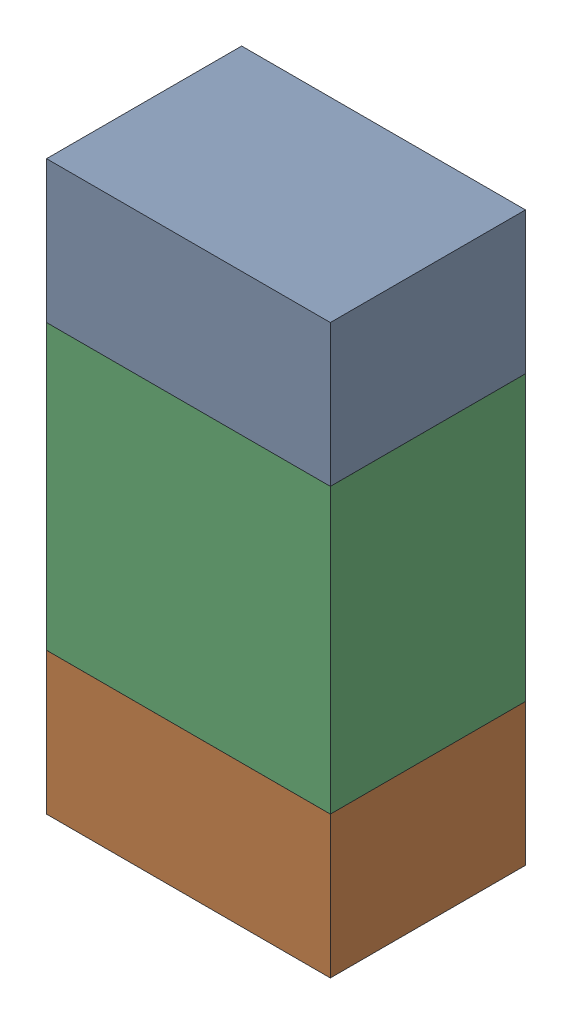
SolidWorks assembly R53, configuration ﾃﾞﾌｫﾙﾄ. Lengths in mm.
Overall size (0.8 1.6 0.55).
6 component instances, 2 part files, 0 mates.
Components (placement in the parent):
- 689261784-1: 689261784 [ﾃﾞﾌｫﾙﾄ] at (44.1999 33.5999 -1.7503) size (0.8 0.4 0.55)
  - Extruded_34-1: Extruded_34 [ﾃﾞﾌｫﾙﾄ] at origin size (0.8 0.4 0.55)
- 689261784-2: 689261784 [ﾃﾞﾌｫﾙﾄ] at (44.1999 32.3999 -1.7503) size (0.8 0.4 0.55)
  - Extruded_34-1: Extruded_34 [ﾃﾞﾌｫﾙﾄ] at origin size (0.8 0.4 0.55)
- 689261648-1: 689261648 [ﾃﾞﾌｫﾙﾄ] at (44.1999 33 -1.7503) size (0.8 0.8 0.55)
  - Extruded_33-1: Extruded_33 [ﾃﾞﾌｫﾙﾄ] at origin size (0.8 0.8 0.55)
